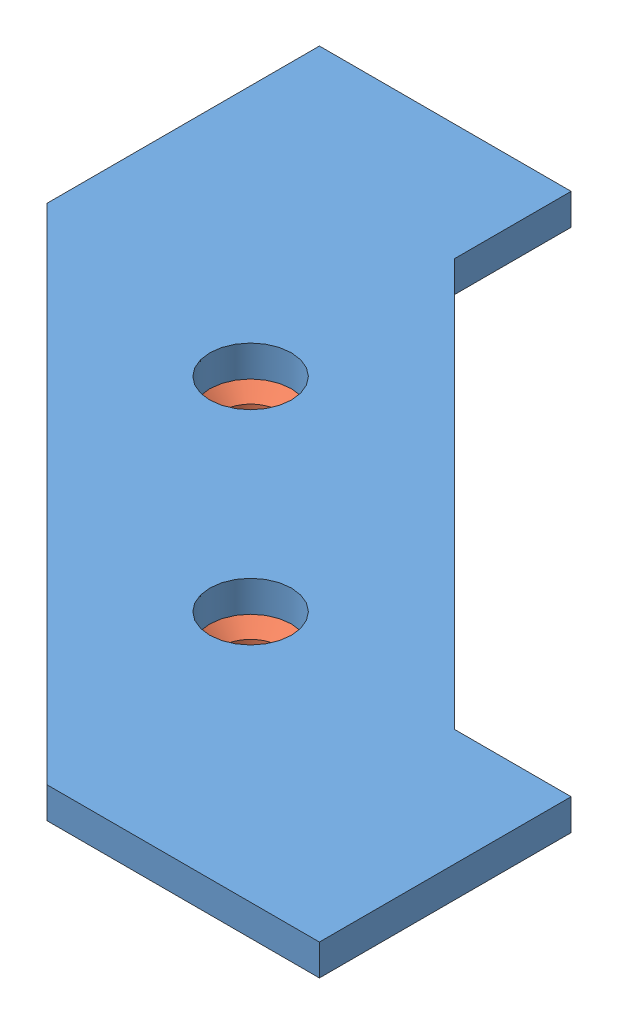
SolidWorks assembly ТП.017.01.05.00 - Закладная задняя, configuration 00. Lengths in mm.
Overall size (99.65 12.4 99.65).
3 component instances, 2 part files, 4 mates.
Components (placement in the parent):
- ТП.017.01.05.01 - Пластина задней закладной (Ст3)-1: ТП.017.01.05.01 - Пластина задней закладной (Ст3) [4мм] at origin size (99.65 4 99.65)
- Гайка (ГОСТ ISO 4032-2014)-1: Гайка (ГОСТ ISO 4032-2014) [Гайка М10 (ГОСТ ISO 4032)] at (-13.0815 -8.2 -13.0815) x (0.955177 0 0.296036) z (0 1 0) size (16 17.77 8.4)
- Гайка (ГОСТ ISO 4032-2014)-2: Гайка (ГОСТ ISO 4032-2014) [Гайка М10 (ГОСТ ISO 4032)] at (13.0815 -8.2 13.0815) x (0.993851 0 0.110723) z (0 1 0) size (16 17.77 8.4)
Mates (geometry in assembly coordinates):
- Совпадение1: coincident: plane of ТП.017.01.05.01 - Пластина задней закладной (Ст3)-1 through (0 -4 0) normal (0 -1 0); plane of Гайка (ГОСТ ISO 4032-2014)-1 through (-10.9204 -4 -20.0543) normal (0 1 0)
- Концентричный1: concentric: cylinder of ТП.017.01.05.01 - Пластина задней закладной (Ст3)-1 through (-13.0815 -4 -13.0815) axis (0 1 0) radius 5.25; cylinder of Гайка (ГОСТ ISO 4032-2014)-1 through (-13.0815 144.5402 -13.0815) axis (0 1 0) radius 3.701
- Совпадение2: coincident: plane of ТП.017.01.05.01 - Пластина задней закладной (Ст3)-1 through (0 -4 0) normal (0 -1 0); plane of Гайка (ГОСТ ISO 4032-2014)-2 through (13.8898 -4 5.8264) normal (0 1 0)
- Концентричный2: concentric: cylinder of ТП.017.01.05.01 - Пластина задней закладной (Ст3)-1 through (13.0815 -4 13.0815) axis (0 1 0) radius 5.25; cylinder of Гайка (ГОСТ ISO 4032-2014)-2 through (13.0815 144.5402 13.0815) axis (0 1 0) radius 3.701
